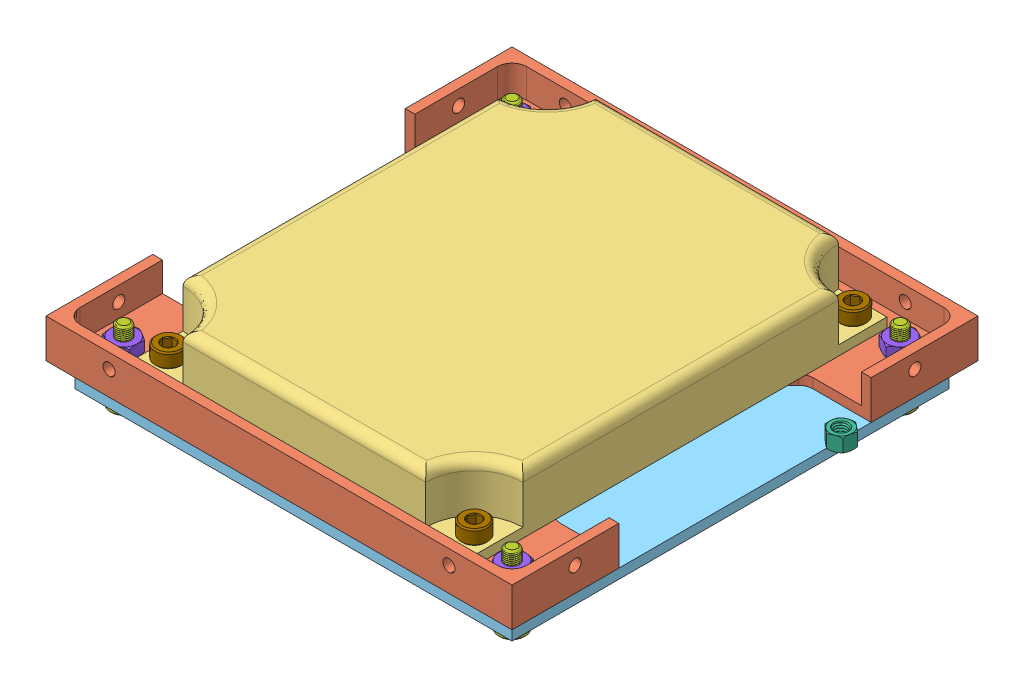
SolidWorks assembly HDD_COMPLETE_ASSEMBLY, configuration Default. Lengths in mm.
Overall size (105.09 26.7 100.93).
26 component instances, 9 part files, 61 mates.
Components (placement in the parent):
- HDD BASE-1: HDD BASE [Default] at (11.0049 90.9152 48.35) x (0 0 1) z (-1 0 0) size (71 7.75 54)
- STANDARD_MOUNTING_BRACKET_HDD-1: STANDARD_MOUNTING_BRACKET_HDD [Default] at (10.9249 88.9152 48) x (1 0 0) z (0 1 0) size (96 96 8)
- HDD_COVER-1: HDD_COVER [Default] at (10.7149 90.9152 48.06) x (0 0 -1) z (1 0 0) size (85 12 70)
- HDD TOP-1: HDD TOP [Default] at (11.0049 93.9152 48.35) x (0 0 1) z (-1 0 0) size (71 5 54)
- HDD PCB-1: HDD PCB [Default] at (10.9249 83.9152 48) x (-1 0 0) z (0 0 -1) size (90 2 90)
- M3_FASTENER_94868A715_18-8 SS FEM THRDED HEX STANDOFF-1: M3_FASTENER_94868A715_18-8 SS FEM THRDED HEX STANDOFF [94868A715] at (50.9249 87.4152 8) x (0.908776 0 0.417284) z (0 1 0) size (15.56 9.34 22.4)
- M3_SCREW_90751A113_METRIC FINE-THREAD 18-18 SS SOCKET HEAD SCREW-1: M3_SCREW_90751A113_METRIC FINE-THREAD 18-18 SS SOCKET HEAD SCREW [90751A113] at (50.9249 95.9152 88) x (-0.795437 0 -0.606037) z (0 1 0) size (5.5 5.5 15.45)
- M3_NUT_91828A211_TYPE 18-8 STAINLESS STEEL HEX NUT-1: M3_NUT_91828A211_TYPE 18-8 STAINLESS STEEL HEX NUT [91828A211] at (50.9249 92.1152 88) x (-0.837169 0 -0.546944) z (0 -1 0) size (5.5 6.35 2.78)
- M3_NUT_91828A211_TYPE 18-8 STAINLESS STEEL HEX NUT-2: M3_NUT_91828A211_TYPE 18-8 STAINLESS STEEL HEX NUT [91828A211] at (50.9249 92.1152 8) x (0.998465 0 -0.055389) z (0 -1 0) size (5.5 6.35 2.78)
- M3_FASTENER_94868A715_18-8 SS FEM THRDED HEX STANDOFF-2: M3_FASTENER_94868A715_18-8 SS FEM THRDED HEX STANDOFF [94868A715] at (50.9249 87.4152 88) x (1 0 0) z (0 -1 0) size (15.56 9.34 22.4)
- M3_SCREW_90751A113_METRIC FINE-THREAD 18-18 SS SOCKET HEAD SCREW-2: M3_SCREW_90751A113_METRIC FINE-THREAD 18-18 SS SOCKET HEAD SCREW [90751A113] at (50.9249 95.9152 8) x (-0.837169 0 -0.546944) z (0 1 0) size (5.5 5.5 15.45)
- M3_SCREW_90751A113_METRIC FINE-THREAD 18-18 SS SOCKET HEAD SCREW-3: M3_SCREW_90751A113_METRIC FINE-THREAD 18-18 SS SOCKET HEAD SCREW [90751A113] at (-29.0751 95.9152 88) x (-0.837169 0 -0.546944) z (0 1 0) size (5.5 5.5 15.45)
- M3_SCREW_90751A113_METRIC FINE-THREAD 18-18 SS SOCKET HEAD SCREW-4: M3_SCREW_90751A113_METRIC FINE-THREAD 18-18 SS SOCKET HEAD SCREW [90751A113] at (-29.0751 95.9152 8) x (-0.837169 0 -0.546944) z (0 1 0) size (5.5 5.5 15.45)
- M3_FASTENER_94868A715_18-8 SS FEM THRDED HEX STANDOFF-3: M3_FASTENER_94868A715_18-8 SS FEM THRDED HEX STANDOFF [94868A715] at (-29.0751 87.4152 88) x (1 0 0) z (0 -1 0) size (15.56 9.34 22.4)
- M3_FASTENER_94868A715_18-8 SS FEM THRDED HEX STANDOFF-4: M3_FASTENER_94868A715_18-8 SS FEM THRDED HEX STANDOFF [94868A715] at (-29.0751 87.4152 8) x (1 0 0) z (0 1 0) size (15.56 9.34 22.4)
- M3_NUT_91828A211_TYPE 18-8 STAINLESS STEEL HEX NUT-3: M3_NUT_91828A211_TYPE 18-8 STAINLESS STEEL HEX NUT [91828A211] at (-29.0751 92.1152 8) x (0.97741 0 0.211352) z (0 1 0) size (5.5 6.35 2.78)
- M3_NUT_91828A211_TYPE 18-8 STAINLESS STEEL HEX NUT-4: M3_NUT_91828A211_TYPE 18-8 STAINLESS STEEL HEX NUT [91828A211] at (-29.0751 92.1152 88) x (1 0 0) z (0 1 0) size (5.5 6.35 2.78)
- M3_FASTENER_94868A715_18-8 SS FEM THRDED HEX STANDOFF-5: M3_FASTENER_94868A715_18-8 SS FEM THRDED HEX STANDOFF [94868A715] at (42.2149 87.4152 9.06) x (1 0 0) z (0 -1 0) size (15.56 9.34 22.4)
- 91292A112_TYPE 18-8 SS SOCKET HEAD CAP SCREW-1: 91292A112_TYPE 18-8 SS SOCKET HEAD CAP SCREW [91292A112] at (42.2149 84.9152 9.06) x (1 0 0) z (0 -1 0) size (5.5 5.5 11.58)
- 91292A112_TYPE 18-8 SS SOCKET HEAD CAP SCREW-2: 91292A112_TYPE 18-8 SS SOCKET HEAD CAP SCREW [91292A112] at (-20.7851 84.9152 9.06) x (0.982082 0 -0.188455) z (0 -1 0) size (5.5 5.5 11.58)
- 91292A112_TYPE 18-8 SS SOCKET HEAD CAP SCREW-4: 91292A112_TYPE 18-8 SS SOCKET HEAD CAP SCREW [91292A112] at (-20.7851 84.9152 87.06) x (0.918365 0 -0.395734) z (0 -1 0) size (5.5 5.5 11.58)
- 91292A112_TYPE 18-8 SS SOCKET HEAD CAP SCREW-7: 91292A112_TYPE 18-8 SS SOCKET HEAD CAP SCREW [91292A112] at (42.2149 84.9152 87.06) x (0.827332 0 -0.561714) z (0 -1 0) size (5.5 5.5 11.58)
- M3_FASTENER_94868A715_18-8 SS FEM THRDED HEX STANDOFF-6: M3_FASTENER_94868A715_18-8 SS FEM THRDED HEX STANDOFF [94868A715] at (42.2149 87.4152 87.06) x (0.982082 0 -0.188455) z (0 -1 0) size (15.56 9.34 22.4)
- M3_FASTENER_94868A715_18-8 SS FEM THRDED HEX STANDOFF-7: M3_FASTENER_94868A715_18-8 SS FEM THRDED HEX STANDOFF [94868A715] at (-20.8661 87.4152 87.06) x (0.918365 0 -0.395734) z (0 -1 0) size (15.56 9.34 22.4)
- M3_FASTENER_94868A715_18-8 SS FEM THRDED HEX STANDOFF-8: M3_FASTENER_94868A715_18-8 SS FEM THRDED HEX STANDOFF [94868A715] at (-20.8661 87.4152 9.06) x (0.8 0 -0.6) z (0 -1 0) size (15.56 9.34 22.4)
- M3_FASTENER_94868A715_18-8 SS FEM THRDED HEX STANDOFF-9: M3_FASTENER_94868A715_18-8 SS FEM THRDED HEX STANDOFF [94868A715] at (56.6364 87.4152 25.8998) x (0.63358 0 -0.773678) z (0 -1 0) size (15.56 9.34 22.4)
Mates (geometry in assembly coordinates):
- Concentric1: concentric: circle of STANDARD_MOUNTING_BRACKET-1; circle of HDD BASE-1
- Coincident1: coincident anti-aligned: plane of STANDARD_MOUNTING_BRACKET-1 through (28.9447 36.4554 85.2336) normal (0 1 0); plane of HDD BASE-1 through (11.0049 89.9152 56.85) normal (0 -1 0)
- Coincident3: coincident anti-aligned: plane of HDD BASE-1 through (11.0049 90.9152 48.35) normal (0 -1 0); plane of STANDARD_MOUNTING_BRACKET_HDD-1 through (10.9249 90.9152 48) normal (0 1 0)
- Coincident13: coincident anti-aligned: plane of HDD BASE-1 through (11.0049 93.9152 48.35) normal (0 1 0); plane of HDD TOP-1 through (11.0049 93.9152 48.35) normal (0 -1 0)
- Concentric18: concentric aligned: cylinder of HDD BASE-1 through (-8.3951 93.9152 77.75) axis (0 1 0) radius 0.55; cylinder of STANDARD_MOUNTING_BRACKET_HDD-1 through (-8.3951 90.9152 77.75) axis (0 1 0) radius 0.55
- Concentric19: concentric aligned: cylinder of HDD BASE-1 through (35.7049 93.9152 80.85) axis (0 1 0) radius 0.55; cylinder of STANDARD_MOUNTING_BRACKET_HDD-1 through (35.7049 90.9152 80.85) axis (0 1 0) radius 0.55
- Concentric22: concentric aligned: cylinder of HDD BASE-1 through (-11.9951 93.9152 15.15) axis (0 1 0) radius 0.55; cylinder of STANDARD_MOUNTING_BRACKET_HDD-1 through (-11.9951 90.9152 15.15) axis (0 1 0) radius 0.55
- Concentric23: concentric aligned: cylinder of HDD BASE-1 through (-8.3951 93.9152 77.75) axis (0 1 0) radius 0.55; cylinder of HDD TOP-1 through (-8.3951 98.9152 77.75) axis (0 1 0) radius 0.55
- Concentric24: concentric aligned: cylinder of HDD BASE-1 through (35.7049 93.9152 80.85) axis (0 1 0) radius 0.55; cylinder of HDD TOP-1 through (35.7049 98.9152 80.85) axis (0 1 0) radius 0.55
- Concentric25: concentric aligned: cylinder of HDD BASE-1 through (35.7049 93.9152 15.15) axis (0 1 0) radius 0.55; cylinder of HDD TOP-1 through (35.7049 98.9152 15.15) axis (0 1 0) radius 0.55
- Concentric26: concentric aligned: cylinder of HDD BASE-1 through (-11.9951 93.9152 15.15) axis (0 1 0) radius 0.55; cylinder of STANDARD_MOUNTING_BRACKET_HDD-1 through (-11.9951 90.9152 15.15) axis (0 1 0) radius 0.55
- Coincident22: coincident anti-aligned: plane of STANDARD_MOUNTING_BRACKET_HDD-1 through (10.9249 90.9152 48) normal (0 1 0); plane of HDD_COVER-1 through (10.7149 90.9152 48.06) normal (0 -1 0)
- Concentric27: concentric aligned: cylinder of STANDARD_MOUNTING_BRACKET_HDD-1 through (42.2149 90.9152 9.06) axis (0 1 0) radius 1.25; cylinder of HDD_COVER-1 through (42.2149 92.9152 9.06) axis (0 1 0) radius 1.25
- Concentric28: concentric aligned: cylinder of STANDARD_MOUNTING_BRACKET_HDD-1 through (42.2149 90.9152 87.06) axis (0 1 0) radius 1.25; cylinder of HDD_COVER-1 through (42.2149 92.9152 87.06) axis (0 1 0) radius 1.25
- Parallel2: parallel anti-aligned: plane of STANDARD_MOUNTING_BRACKET_HDD-1 through (10.9249 88.9152 48) normal (0 -1 0); plane of HDD PCB-1 through (10.9249 85.9152 48) normal (0 1 0)
- Parallel3: parallel aligned: plane of STANDARD_MOUNTING_BRACKET_HDD-1 through (-37.0751 96.9152 0) normal (0 0 -1); plane of HDD PCB-1 through (55.9249 85.9152 3) normal (0 0 -1)
- Coincident31: coincident anti-aligned: plane of STANDARD_MOUNTING_BRACKET_HDD-1 through (-37.0751 96.9152 0) normal (0 0 -1)
- Parallel4: parallel aligned: plane of STANDARD_MOUNTING_BRACKET_HDD-1 through (10.9249 90.9152 48) normal (0 1 0)
- Concentric38: concentric anti-aligned: circle of STANDARD_MOUNTING_BRACKET_HDD-1; circle of 94868A715_18-8 SS FEM THRDED HEX STANDOFF-1
- Coincident40: coincident anti-aligned: plane of STANDARD_MOUNTING_BRACKET_HDD-1 through (10.9249 88.9152 48) normal (0 -1 0); plane of M3_FASTENER_94868A715_18-8 SS FEM THRDED HEX STANDOFF-1 through (52.0091 88.9152 5.6389) normal (0 1 0)
- Concentric39: concentric anti-aligned: circle of HDD PCB-1; circle of 94868A715_18-8 SS FEM THRDED HEX STANDOFF-1
- Coincident46: coincident anti-aligned: plane of HDD PCB-1 through (10.9249 85.9152 48) normal (0 1 0); plane of M3_FASTENER_94868A715_18-8 SS FEM THRDED HEX STANDOFF-1 through (52.0091 85.9152 5.6389) normal (0 -1 0)
- Concentric41: concentric aligned: circle of STANDARD_MOUNTING_BRACKET_HDD-1; circle of 90751A113_METRIC FINE-THREAD 18-18 SS SOCKET HEAD SCREW-1
- Coincident48: coincident anti-aligned: plane of HDD PCB-1 through (10.9249 83.9152 48) normal (0 -1 0); plane of M3_SCREW_90751A113_METRIC FINE-THREAD 18-18 SS SOCKET HEAD SCREW-1 through (50.9249 83.9152 88) normal (0 1 0)
- Coincident49: coincident anti-aligned: plane of STANDARD_MOUNTING_BRACKET_HDD-1 through (10.9249 90.9152 48) normal (0 1 0); plane of M3_NUT_91828A211_TYPE 18-8 STAINLESS STEEL HEX NUT-1 through (54.0955 90.9152 88.1749) normal (0 -1 0)
- Concentric42: concentric aligned: circle of 90751A113_METRIC FINE-THREAD 18-18 SS SOCKET HEAD SCREW-1; circle of 91828A211_TYPE 18-8 STAINLESS STEEL HEX NUT (1)-1
- Coincident50: coincident anti-aligned: plane of STANDARD_MOUNTING_BRACKET_HDD-1 through (10.9249 90.9152 48) normal (0 1 0); plane of M3_NUT_91828A211_TYPE 18-8 STAINLESS STEEL HEX NUT-2 through (48.2671 90.9152 9.7376) normal (0 -1 0)
- Concentric44: concentric anti-aligned: circle of 91828A211_TYPE 18-8 STAINLESS STEEL HEX NUT (1)-1; circle of 94868A715_18-8 SS FEM THRDED HEX STANDOFF-2
- Coincident51: coincident anti-aligned: plane of HDD PCB-1 through (10.9249 85.9152 48) normal (0 1 0); plane of M3_FASTENER_94868A715_18-8 SS FEM THRDED HEX STANDOFF-2 through (50.9249 85.9152 90.5981) normal (0 -1 0)
- Concentric45: concentric aligned: circle of HDD PCB-1; circle of M3_SCREW_90751A113_METRIC FINE-THREAD 18-18 SS SOCKET HEAD SCREW-2
- Coincident52: coincident anti-aligned: plane of HDD PCB-1 through (10.9249 83.9152 48) normal (0 -1 0); plane of M3_SCREW_90751A113_METRIC FINE-THREAD 18-18 SS SOCKET HEAD SCREW-2 through (50.9249 83.9152 8) normal (0 1 0)
- Concentric46: concentric aligned: circle of HDD PCB-1; circle of M3_SCREW_90751A113_METRIC FINE-THREAD 18-18 SS SOCKET HEAD SCREW-4
- Coincident53: coincident anti-aligned: plane of HDD PCB-1 through (10.9249 83.9152 48) normal (0 -1 0); plane of M3_SCREW_90751A113_METRIC FINE-THREAD 18-18 SS SOCKET HEAD SCREW-4 through (-29.0751 83.9152 8) normal (0 1 0)
- Concentric47: concentric aligned: circle of HDD PCB-1; circle of M3_SCREW_90751A113_METRIC FINE-THREAD 18-18 SS SOCKET HEAD SCREW-3
- Coincident54: coincident anti-aligned: plane of HDD PCB-1 through (10.9249 83.9152 48) normal (0 -1 0); plane of M3_SCREW_90751A113_METRIC FINE-THREAD 18-18 SS SOCKET HEAD SCREW-3 through (-29.0751 83.9152 88) normal (0 1 0)
- Concentric48: concentric anti-aligned: circle of M3_SCREW_90751A113_METRIC FINE-THREAD 18-18 SS SOCKET HEAD SCREW-3; circle of M3_FASTENER_94868A715_18-8 SS FEM THRDED HEX STANDOFF-3
- Coincident55: coincident anti-aligned: plane of HDD PCB-1 through (10.9249 85.9152 48) normal (0 1 0); plane of M3_FASTENER_94868A715_18-8 SS FEM THRDED HEX STANDOFF-3 through (-29.0751 85.9152 90.5981) normal (0 -1 0)
- Concentric49: concentric aligned: circle of M3_SCREW_90751A113_METRIC FINE-THREAD 18-18 SS SOCKET HEAD SCREW-4; circle of M3_FASTENER_94868A715_18-8 SS FEM THRDED HEX STANDOFF-4
- Coincident56: coincident anti-aligned: plane of HDD PCB-1 through (10.9249 85.9152 48) normal (0 1 0); plane of M3_FASTENER_94868A715_18-8 SS FEM THRDED HEX STANDOFF-4 through (-29.0751 85.9152 5.4019) normal (0 -1 0)
- Concentric50: concentric anti-aligned: circle of M3_SCREW_90751A113_METRIC FINE-THREAD 18-18 SS SOCKET HEAD SCREW-4; circle of M3_NUT_91828A211_TYPE 18-8 STAINLESS STEEL HEX NUT-3
- Coincident57: coincident anti-aligned: plane of STANDARD_MOUNTING_BRACKET_HDD-1 through (10.9249 90.9152 48) normal (0 1 0); plane of M3_NUT_91828A211_TYPE 18-8 STAINLESS STEEL HEX NUT-3 through (-31.4274 90.9152 5.8669) normal (0 -1 0)
- Concentric51: concentric anti-aligned: circle of M3_SCREW_90751A113_METRIC FINE-THREAD 18-18 SS SOCKET HEAD SCREW-3; circle of M3_NUT_91828A211_TYPE 18-8 STAINLESS STEEL HEX NUT-4
- Coincident58: coincident anti-aligned: plane of STANDARD_MOUNTING_BRACKET_HDD-1 through (10.9249 90.9152 48) normal (0 1 0); plane of M3_NUT_91828A211_TYPE 18-8 STAINLESS STEEL HEX NUT-4 through (-31.8251 90.9152 86.4123) normal (0 -1 0)
- Concentric52: concentric aligned: circle of M3_NUT_91828A211_TYPE 18-8 STAINLESS STEEL HEX NUT-2; circle of M3_SCREW_90751A113_METRIC FINE-THREAD 18-18 SS SOCKET HEAD SCREW-2
- Coincident59: coincident anti-aligned: plane of HDD_COVER-1 through (45.7149 92.9152 5.56) normal (0 1 0); plane of 91292A112_TYPE 18-8 SS SOCKET HEAD CAP SCREW-1 through (42.2149 92.9152 9.06) normal (0 -1 0)
- Concentric53: concentric anti-aligned: cylinder of HDD_COVER-1 through (42.2149 92.9152 9.06) axis (0 1 0) radius 1.25; circle of 91292A112_TYPE 18-8 SS SOCKET HEAD CAP SCREW-1
- Coincident60: coincident anti-aligned: plane of HDD_COVER-1 through (-24.2851 92.9152 5.56) normal (0 1 0); plane of 91292A112_TYPE 18-8 SS SOCKET HEAD CAP SCREW-2 through (-20.7851 92.9152 9.06) normal (0 -1 0)
- Concentric55: concentric anti-aligned: cylinder of HDD_COVER-1 through (-20.7851 92.9152 9.06) axis (0 1 0) radius 1.25; circle of 91292A112_TYPE 18-8 SS SOCKET HEAD CAP SCREW-2
- Coincident61: coincident anti-aligned: plane of HDD_COVER-1 through (-24.2851 92.9152 90.56) normal (0 1 0); plane of 91292A112_TYPE 18-8 SS SOCKET HEAD CAP SCREW-4 through (-20.7851 92.9152 87.06) normal (0 -1 0)
- Concentric56: concentric anti-aligned: cylinder of HDD_COVER-1 through (-20.7851 92.9152 87.06) axis (0 1 0) radius 1.25; circle of 91292A112_TYPE 18-8 SS SOCKET HEAD CAP SCREW-4
- Coincident63: coincident anti-aligned: plane of HDD_COVER-1 through (45.7149 92.9152 90.56) normal (0 1 0); plane of 91292A112_TYPE 18-8 SS SOCKET HEAD CAP SCREW-7 through (42.2149 92.9152 87.06) normal (0 -1 0)
- Concentric58: concentric anti-aligned: cylinder of HDD_COVER-1 through (42.2149 92.9152 87.06) axis (0 1 0) radius 1.25; circle of 91292A112_TYPE 18-8 SS SOCKET HEAD CAP SCREW-7
- Coincident64: coincident anti-aligned: plane of STANDARD_MOUNTING_BRACKET_HDD-1 through (10.9249 88.9152 48) normal (0 -1 0); plane of M3_FASTENER_94868A715_18-8 SS FEM THRDED HEX STANDOFF-5 through (42.2149 88.9152 11.6581) normal (0 1 0)
- Concentric59: concentric anti-aligned: circle of STANDARD_MOUNTING_BRACKET_HDD-1; circle of M3_FASTENER_94868A715_18-8 SS FEM THRDED HEX STANDOFF-5
- Coincident65: coincident anti-aligned: plane of STANDARD_MOUNTING_BRACKET_HDD-1 through (10.9249 88.9152 48) normal (0 -1 0); plane of M3_FASTENER_94868A715_18-8 SS FEM THRDED HEX STANDOFF-6 through (42.7046 88.9152 89.6115) normal (0 1 0)
- Concentric60: concentric anti-aligned: circle of STANDARD_MOUNTING_BRACKET_HDD-1; circle of M3_FASTENER_94868A715_18-8 SS FEM THRDED HEX STANDOFF-6
- Coincident66: coincident anti-aligned: plane of STANDARD_MOUNTING_BRACKET_HDD-1 through (10.9249 88.9152 48) normal (0 -1 0); plane of M3_FASTENER_94868A715_18-8 SS FEM THRDED HEX STANDOFF-7 through (-19.8379 88.9152 89.446) normal (0 1 0)
- Concentric61: concentric anti-aligned: circle of STANDARD_MOUNTING_BRACKET_HDD-1; circle of M3_FASTENER_94868A715_18-8 SS FEM THRDED HEX STANDOFF-7
- Coincident67: coincident anti-aligned: plane of STANDARD_MOUNTING_BRACKET_HDD-1 through (10.9249 88.9152 48) normal (0 -1 0); plane of M3_FASTENER_94868A715_18-8 SS FEM THRDED HEX STANDOFF-8 through (-19.3072 88.9152 11.1385) normal (0 1 0)
- Concentric62: concentric anti-aligned: circle of STANDARD_MOUNTING_BRACKET_HDD-1; circle of M3_FASTENER_94868A715_18-8 SS FEM THRDED HEX STANDOFF-8
- Coincident68: coincident anti-aligned: plane of STANDARD_MOUNTING_BRACKET_HDD-1 through (10.9249 88.9152 48) normal (0 -1 0); plane of M3_FASTENER_94868A715_18-8 SS FEM THRDED HEX STANDOFF-9 through (58.6465 88.9152 27.5459) normal (0 1 0)
